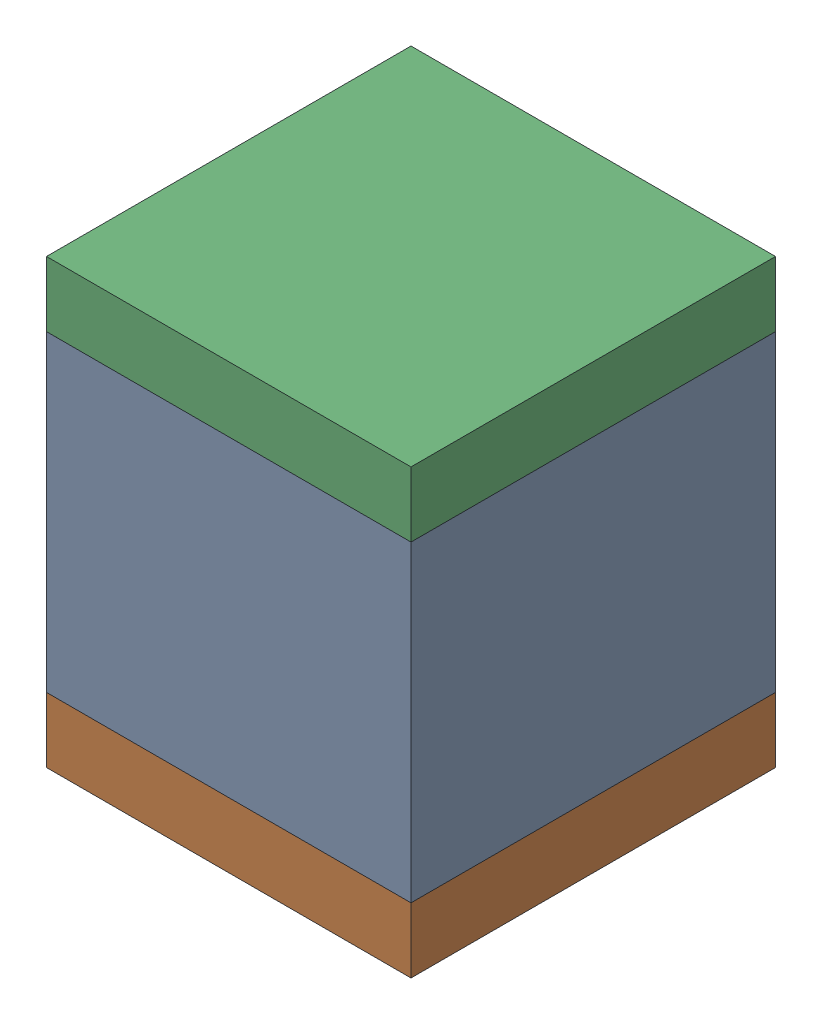
SolidWorks assembly C415PCB, configuration Default. Lengths in mm.
Overall size (2.8 3.4 2.8).
6 component instances, 2 part files, 0 mates.
Components (placement in the parent):
- 846484376-1: 846484376 [Default] at (81.39 92 0) size (2.8 2.4 2.8)
  - Extruded_31-1: Extruded_31 [Default] at origin size (2.8 2.4 2.8)
- 846484512-1: 846484512 [Default] at (81.39 90.55 0) size (2.8 0.5 2.8)
  - Extruded_32-1: Extruded_32 [Default] at origin size (2.8 0.5 2.8)
- 846484512-2: 846484512 [Default] at (81.39 93.45 0) size (2.8 0.5 2.8)
  - Extruded_32-1: Extruded_32 [Default] at origin size (2.8 0.5 2.8)
